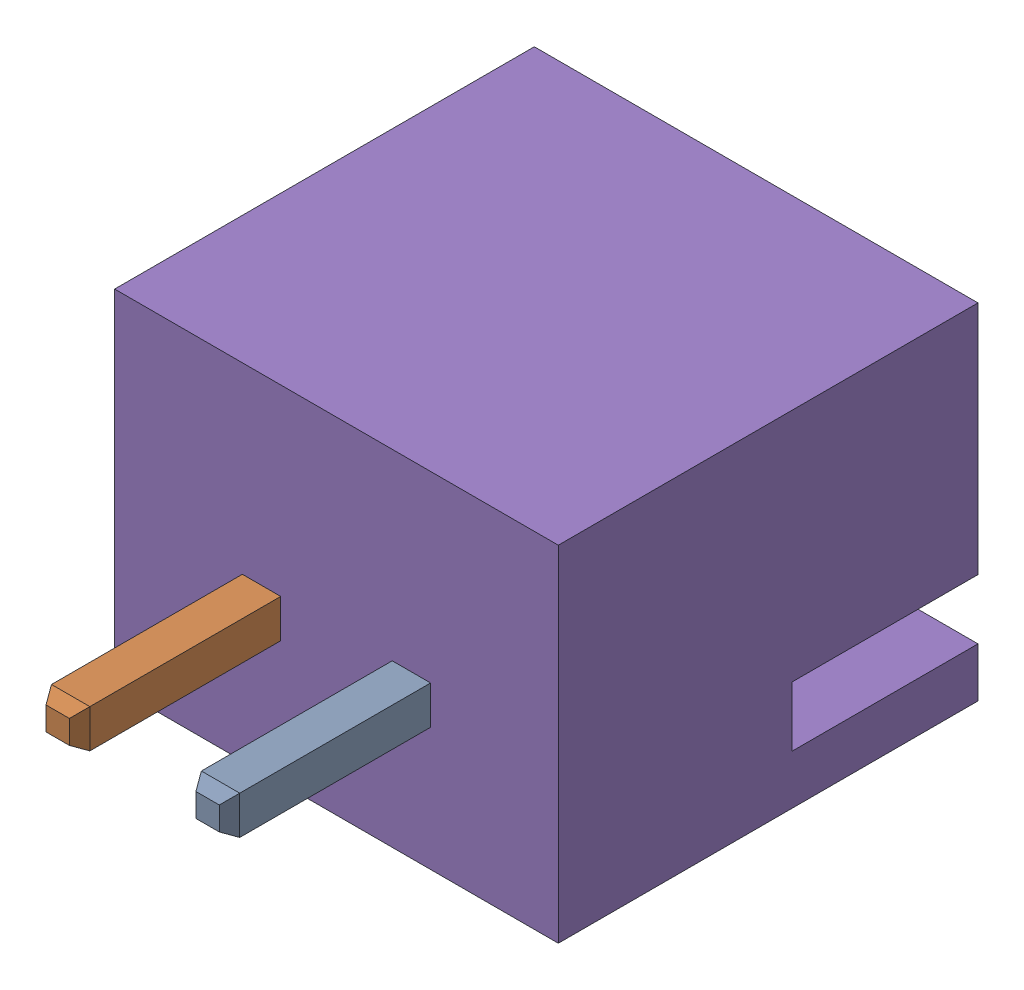
SolidWorks assembly P1-1, configuration Default. Lengths in mm.
Overall size (7.4 5.75 10.4).
6 component instances, 5 part files, 0 mates.
Components (placement in the parent):
- P1-subassembly-1-1-1: P1-subassembly-1-1 [Default] at (131.5051 81.6569 -0.3912) x (-1 0 0) z (0 -1 0) size (7.4 10.4 5.75)
  - User Library-JST B2B-XH-A-5-1: User Library-JST B2B-XH-A-5 [Default] at origin size (0.64 3.4 0.64)
  - User Library-JST B2B-XH-A-6-1: User Library-JST B2B-XH-A-6 [Default] at origin size (0.64 3.4 0.64)
  - User Library-JST B2B-XH-A-7-1: User Library-JST B2B-XH-A-7 [Default] at origin size (0.64 4.5 0.64)
  - User Library-JST B2B-XH-A-8-1: User Library-JST B2B-XH-A-8 [Default] at origin size (0.64 4.5 0.64)
  - User Library-JST B2B-XH-A-9-1: User Library-JST B2B-XH-A-9 [Default] at origin size (7.4 7 5.75)
